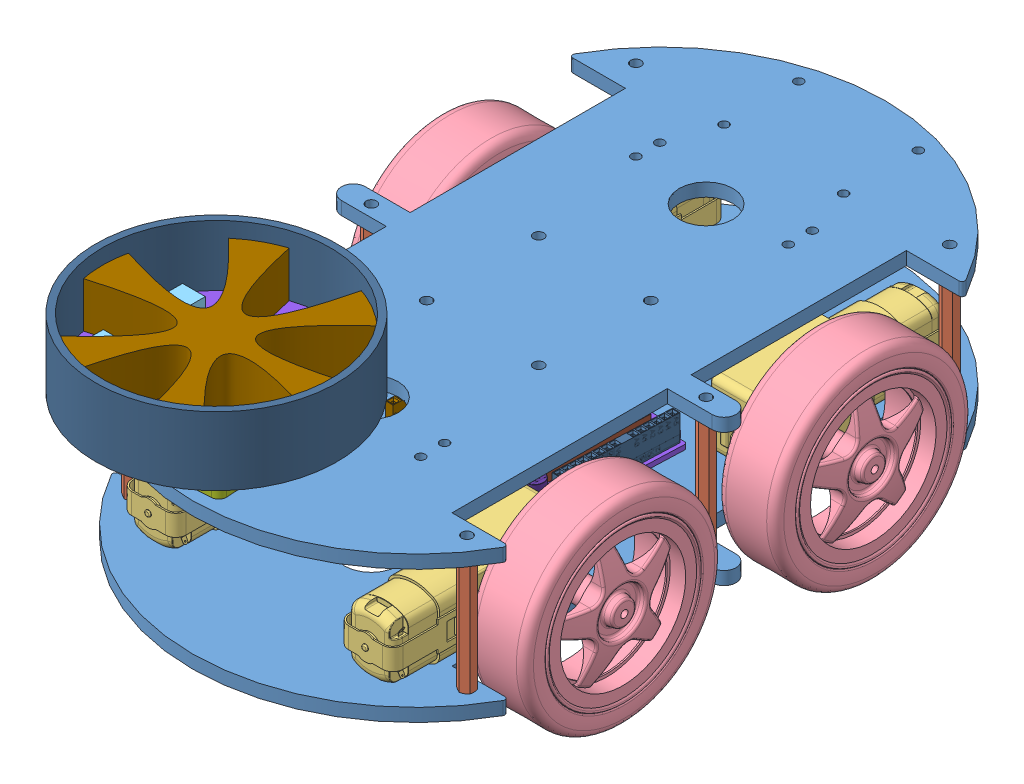
SolidWorks assembly new mechanical dispensing system, configuration Default. Lengths in mm.
Overall size (144 125.53 276.26).
42 component instances, 28 part files, 52 mates.
Components (placement in the parent):
- Base Plate-1: Base Plate [Default] at origin size (132 4.4 231.81)
- Long Hex Nut-1: Long Hex Nut [B18.2.4.1M - Hex nut, Style 1,  M3 x 0.5 --D-N] at (-56 44.4 80) x (-0.471141 0 -0.882058) z (0 1 0) size (4.5 5.2 40)
- Long Hex Nut-5: Long Hex Nut [B18.2.4.1M - Hex nut, Style 1,  M3 x 0.5 --D-N] at (56 44.4 0) x (1 0 0) z (0 1 0) size (4.5 5.2 40)
- Long Hex Nut-6: Long Hex Nut [B18.2.4.1M - Hex nut, Style 1,  M3 x 0.5 --D-N] at (56 44.4 80) x (1 0 0) z (0 1 0) size (4.5 5.2 40)
- Long Hex Nut-7: Long Hex Nut [B18.2.4.1M - Hex nut, Style 1,  M3 x 0.5 --D-N] at (52.5 44.4 -85) x (1 0 0) z (0 1 0) size (4.5 5.2 40)
- Long Hex Nut-8: Long Hex Nut [B18.2.4.1M - Hex nut, Style 1,  M3 x 0.5 --D-N] at (-52.5 44.4 -85) x (1 0 0) z (0 1 0) size (4.5 5.2 40)
- Long Hex Nut-9: Long Hex Nut [B18.2.4.1M - Hex nut, Style 1,  M3 x 0.5 --D-N] at (-56 44.4 0) x (1 0 0) z (0 1 0) size (4.5 5.2 40)
- Base Plate-2: Base Plate [Default] at (0 44.4 0) size (132 4.4 231.81)
- Motor-1: Motor [Predeterminado] at (37.6 15.65 -77.2352) x (0 0 1) z (-1 0 0) size (69.7 22.5 36.8)
- Motor-2: Motor [Predeterminado] at (37.6 15.65 80.1311) x (0 0 -1) z (1 0 0) size (69.7 22.5 36.8)
- Motor-3: Motor [Predeterminado] at (-37.6 15.65 77.5479) x (0 0 -1) z (1 0 0) size (69.7 22.5 36.8)
- Motor-4: Motor [Predeterminado] at (-37.6 15.65 -76) x (0 0 1) z (-1 0 0) size (69.7 22.5 36.8)
- Wheel-1: Wheel [Predeterminado] at (-52 15.65 -39.2) x (-1 0 0) z (0 -0.685524 -0.72805) size (25 66 66)
- Wheel-2: Wheel [Predeterminado] at (52 15.65 -40.4352) x (1 0 0) z (0 0.941369 0.337378) size (25 66 66)
- Wheel-3: Wheel [Predeterminado] at (-52 15.65 40.7479) x (-1 0 0) z (0 -0.719414 -0.694582) size (25 66 66)
- Wheel-4: Wheel [Predeterminado] at (52 15.65 43.3311) x (1 0 0) z (0 -0.162012 0.986789) size (25 66 66)
- cube-2: cube [Default] at (-27.6013 78.01 114.2712) size (7.62 7.62 7.62)
- cube-7: cube [Default] at (-27.7204 78.01 87.6337) size (7.62 7.62 7.62)
- Ardi_UNO.STEP-1: Ardi_UNO.STEP [Default] at (-32.6159 2.8 38.091) x (0.039139 0 -0.999234) z (0 1 0) size (76.36 53.4 14.04)
  - Pins_3fach_q_001.STEP-1: Pins_3fach_q_001.STEP [Default] at (64.19 -23.29 3.21) size (5.08 7.62 11.94)
  - Pins_3fach_q_002.STEP-1: Pins_3fach_q_002.STEP [Default] at (15.78 -9.32 3.21) x (0 1 0) z (0 0 1) size (5.08 7.62 11.94)
  - Ardi_UNO_Platine_001.STEP-1: Ardi_UNO_Platine_001.STEP [Default] at origin size (69 53.4 1.61)
  - Headers_digital_001.STEP-1: Headers_digital_001.STEP [Default] at origin size (47.8 2.55 10.95)
  - Headers_Analog_001.STEP-1: Headers_Analog_001.STEP [Default] at origin size (38.85 2.55 10.95)
  - atmega328_socket_001.STEP-1: atmega328_socket_001.STEP [Default] at origin size (35.5 10 6.2)
  - atmega328_001.STEP-1: atmega328_001.STEP [Default] at origin size (35.36 8.18 5.99)
  - resetButton UNO_001.STEP-1: resetButton UNO_001.STEP [Default] at origin size (8.5 6.5 3.8)
  - USB_typeB_001.STEP-1: USB_typeB_001.STEP [Default] at (8.29 -16.56 3.2) x (0 -1 0) z (0 0 1) size (12.06 16.98 13.98)
  - Stromanschluss_arduino UNO_001.STEP-1: Stromanschluss_arduino UNO_001.STEP [Default] at origin size (14.2 9.2 13)
  - Kondensator_A8-47-25V_001.STEP-1: Kondensator_A8-47-25V_001.STEP [Default] at (-0.25 0 0) size (6.5 7.5 5)
  - Kondensator_A8-47-25V_002.STEP-1: Kondensator_A8-47-25V_002.STEP [Default] at (6.5 0 0) size (6.5 7.5 5)
  - Quarz_Arduino_16_001.STEP-1: Quarz_Arduino_16_001.STEP [Default] at origin size (12.5 4.5 5.2)
  - Transistor Arduino UNO_001.STEP-1: Transistor Arduino UNO_001.STEP [Default] at origin size (6.8 6.5 1.6)
  - LED Arduino UNO gelb_001.STEP-1: LED Arduino UNO gelb_001.STEP [Default] at origin size (2 1 0.5)
  - LED Arduino UNO gelb_002.STEP-1: LED Arduino UNO gelb_002.STEP [Default] at (0 -6 0) size (2 1 0.5)
  - LED Arduino UNO gelb_003.STEP-1: LED Arduino UNO gelb_003.STEP [Default] at (0 -8 0) size (2 1 0.5)
  - LED Arduino UNO gr__n_001.STEP-1: LED Arduino UNO gr__n_001.STEP [Default] at (30.5 -6 0) size (2 1 0.5)
  - achterTeil_001.STEP-1: achterTeil_001.STEP [Default] at origin size (3.2 4.7 0.8)
- stepper motor-2: stepper motor [Default] at (-4.4982 66.58 103.3442) x (-0.060615 0 -0.998161) z (0 -1 0) size (17.78 17.78 25.4)
- dispensing system disc-1: dispensing system disc [Default] at (-4.4982 71.66 103.3442) x (-0.818866 0 0.573984) z (0 1 0) size (76.2 76.19 2.54)
- new dispensing system-1: new dispensing system [Default] at (-4.4982 74.2 103.3442) x (-0.999945 0 -0.010458) z (0 1 0) size (76.2 72.18 15.24)
- dispensing shell-1: dispensing shell [Default] at (-4.4982 94.52 103.3442) x (0.738984 0 -0.673723) z (0 -1 0) size (80.71 80.71 22.86)
Mates (geometry in assembly coordinates):
- Coincident11: coincident anti-aligned: plane of Base Plate-1 through (0 4.4 0) normal (0 1 0); plane of Long Hex Nut-1 through (-53.8799 4.4 83.9693) normal (0 -1 0)
- Concentric1: concentric anti-aligned: circle of Base Plate-1; circle of Long Hex Nut-1
- Concentric21: concentric anti-aligned: cylinder of Base Plate-1 through (-18.75 0 18.75) axis (0 -1 0) radius 1.75; cylinder of Long Hex Nut-2 through (-18.75 19.3625 18.75) axis (0 1 0) radius 1.5
- Coincident21: coincident anti-aligned: plane of Base Plate-1 through (0 4.4 0) normal (0 1 0); plane of Long Hex Nut-2 through (-23.25 4.4 18.75) normal (0 -1 0)
- Coincident31: coincident anti-aligned: plane of Base Plate-1 through (0 4.4 0) normal (0 1 0); plane of Long Hex Nut-3 through (-27.4259 4.4 -36.2608) normal (0 -1 0)
- Concentric31: concentric anti-aligned: cylinder of Base Plate-1 through (20 0 -82) axis (0 -1 0) radius 1.5; cylinder of Long Hex Nut-4 through (20 19.3625 -82) axis (0 1 0) radius 1.5
- Coincident41: coincident anti-aligned: plane of Base Plate-1 through (0 4.4 0) normal (0 1 0); plane of Long Hex Nut-4 through (15.5 4.4 -82) normal (0 -1 0)
- Concentric41: concentric anti-aligned: cylinder of Base Plate-1 through (56 0 0) axis (0 -1 0) radius 1.75; cylinder of Long Hex Nut-5 through (56 19.3625 0) axis (0 1 0) radius 1.5
- Coincident51: coincident anti-aligned: plane of Base Plate-1 through (0 4.4 0) normal (0 1 0); plane of Long Hex Nut-5 through (51.5 4.4 0) normal (0 -1 0)
- Concentric51: concentric anti-aligned: cylinder of Base Plate-1 through (56 0 80) axis (0 -1 0) radius 1.75; cylinder of Long Hex Nut-6 through (56 19.3625 80) axis (0 1 0) radius 1.5
- Coincident61: coincident anti-aligned: plane of Base Plate-1 through (0 4.4 0) normal (0 1 0); plane of Long Hex Nut-6 through (51.5 4.4 80) normal (0 -1 0)
- Concentric81: concentric anti-aligned: cylinder of Base Plate-1 through (52.5 0 -85) axis (0 -1 0) radius 1.75; cylinder of Long Hex Nut-7 through (52.5 19.3625 -85) axis (0 1 0) radius 1.5
- Coincident71: coincident anti-aligned: plane of Base Plate-1 through (0 4.4 0) normal (0 1 0); plane of Long Hex Nut-7 through (48 4.4 -85) normal (0 -1 0)
- Concentric91: concentric anti-aligned: cylinder of Base Plate-1 through (-52.5 0 -85) axis (0 -1 0) radius 1.75; cylinder of Long Hex Nut-8 through (-52.5 19.3625 -85) axis (0 1 0) radius 1.5
- Coincident81: coincident anti-aligned: plane of Base Plate-1 through (0 4.4 0) normal (0 1 0); plane of Long Hex Nut-8 through (-57 4.4 -85) normal (0 -1 0)
- Concentric101: concentric anti-aligned: cylinder of Base Plate-1 through (-56 0 0) axis (0 -1 0) radius 1.75; cylinder of Long Hex Nut-9 through (-56 19.3625 0) axis (0 1 0) radius 1.5
- Coincident91: coincident anti-aligned: plane of Base Plate-1 through (0 4.4 0) normal (0 1 0); plane of Long Hex Nut-9 through (-60.5 4.4 0) normal (0 -1 0)
- Concentric11: concentric anti-aligned: circle of Long Hex Nut-1; cylinder of Base Plate-2 through (-56 44.4 80) axis (0 -1 0) radius 1.75
- Concentric12: concentric aligned: circle of Long Hex Nut-7; cylinder of Base Plate-2 through (52.5 44.4 -85) axis (0 -1 0) radius 1.75
- Coincident10: coincident anti-aligned: plane of Long Hex Nut-7 through (48 44.4 -85) normal (0 1 0); plane of Base Plate-2 through (0 44.4 0) normal (0 -1 0)
- Coincident11: coincident anti-aligned: plane of Base Plate-1 through (0 4.4 0) normal (0 1 0); plane of Motor-1 through (28.2 4.4 -31.5352) normal (0 -1 0)
- Coincident12: coincident aligned: plane of Base Plate-1 through (47 4.4 -76) normal (1 0 0); plane of Motor-1 through (47 6.7 -31.5352) normal (1 0 0)
- Coincident13: coincident anti-aligned: plane of Base Plate-1 through (0 4.4 0) normal (0 1 0); plane of Motor-4 through (-47 4.4 -30.3) normal (0 -1 0)
- Coincident14: coincident aligned: plane of Base Plate-1 through (-47 4.4 -76) normal (-1 0 0); plane of Motor-4 through (-47 6.7 -30.3) normal (-1 0 0)
- Coincident15: coincident anti-aligned: plane of Base Plate-1 through (0 4.4 0) normal (0 1 0); plane of Motor-3 through (-28.2 4.4 31.8479) normal (0 -1 0)
- Coincident16: coincident aligned: plane of Base Plate-1 through (-47 4.4 76) normal (-1 0 0); plane of Motor-3 through (-47 6.7 31.8479) normal (-1 0 0)
- Coincident17: coincident anti-aligned: plane of Base Plate-1 through (0 4.4 0) normal (0 1 0); plane of Motor-2 through (47 4.4 34.4311) normal (0 -1 0)
- Coincident18: coincident aligned: plane of Base Plate-1 through (47 4.4 76) normal (1 0 0); plane of Motor-2 through (47 6.7 34.4311) normal (1 0 0)
- Concentric13: concentric aligned: circle of Motor-2; circle of Wheel-4
- Coincident24: coincident aligned: circle of Motor-1; plane of Wheel-2 through (47 15.65 -40.4352) normal (-1 0 0)
- Parallel1: parallel anti-aligned: plane of Motor-1 through (56 15.65 -77.2352) normal (1 0 0); plane of Wheel-2 through (47 15.65 -40.4352) normal (-1 0 0)
- Coincident26: coincident anti-aligned: plane of Motor-2 through (47 6.7 34.4311) normal (1 0 0); plane of Wheel-4 through (47 15.65 43.3311) normal (-1 0 0)
- Coincident29: coincident anti-aligned: plane of Motor-1 through (47 6.7 -31.5352) normal (1 0 0); plane of Wheel-2 through (47 15.65 -40.4352) normal (-1 0 0)
- Concentric14: concentric anti-aligned: circle of Motor-1; circle of Wheel-2
- Concentric15: concentric aligned: circle of Motor-4; circle of Wheel-1
- Coincident30: coincident anti-aligned: plane of Motor-4 through (-47 6.7 -30.3) normal (-1 0 0); plane of Wheel-1 through (-47 15.65 -39.2) normal (1 0 0)
- Concentric16: concentric anti-aligned: circle of Motor-3; circle of Wheel-3
- Coincident31: coincident anti-aligned: plane of Motor-3 through (-47 6.7 31.8479) normal (-1 0 0); plane of Wheel-3 through (-47 15.65 40.7479) normal (1 0 0)
- Coincident35: coincident aligned: line of Base Plate-1 through (-47 4.4 -76) axis (0 -1 0); line of Motor-4 through (-47 21.9222 -76) axis (0 -1 0)
- Parallel4: parallel anti-aligned: line of Base Plate-1 through (47 4.4 -76) axis (0 -1 0); line of Motor-1 through (45.5 9.3778 -77.2352) axis (0 1 0)
- Coincident96: coincident anti-aligned: plane of Base Plate-1 through (0 4.4 0) normal (0 1 0); plane of Ardi_UNO.STEP-1/Ardi_UNO_Platine_001.STEP-1 through (-4.4777 4.4 5.4847) normal (0 -1 0)
- Coincident97: coincident: cylinder of Motor-4 through (-28.7 24.6 -28.5) axis (0 -1 0) radius 0.5; line of Ardi_UNO.STEP-1/Ardi_UNO_Platine_001.STEP-1 through (-28.2467 4.4 -28.2889) axis (0 1 0)
- Coincident98: coincident anti-aligned: plane of Base Plate-2 through (0 48.8 0) normal (0 1 0); plane of stepper motor-2 through (-4.4982 48.8 103.3442) normal (0 -1 0)
- Concentric102: concentric anti-aligned: cylinder of stepper motor-2 through (-4.4982 74.2 103.3442) axis (0 -1 0) radius 1.5744; cylinder of dispensing system disc-1 through (-4.4982 71.66 103.3442) axis (0 1 0) radius 1.524
- Coincident99: coincident anti-aligned: plane of dispensing system disc-1 through (-4.4982 74.2 103.3442) normal (0 1 0); plane of new dispensing system-1 through (-4.4982 74.2 103.3442) normal (0 -1 0)
- Coincident100: coincident anti-aligned: plane of stepper motor-2 through (-4.4982 74.2 103.3442) normal (0 1 0); plane of new dispensing system-1 through (-4.4982 74.2 103.3442) normal (0 -1 0)
- Coincident102: coincident anti-aligned: plane of cube-2 through (-31.4113 74.2 121.8912) normal (0 -1 0); plane of dispensing system disc-1 through (-4.4982 74.2 103.3442) normal (0 1 0)
- Coincident103: coincident anti-aligned: plane of cube-7 through (-31.5304 74.2 95.2537) normal (0 -1 0); plane of dispensing system disc-1 through (-4.4982 74.2 103.3442) normal (0 1 0)
- Coincident104: coincident aligned: plane of dispensing system disc-1 through (-4.4982 71.66 103.3442) normal (0 -1 0); plane of dispensing shell-1 through (-4.4982 71.66 103.3442) normal (0 -1 0)
- Parallel5: parallel aligned: plane of new dispensing system-1 through (-4.5999 89.44 113.0682) normal (0 1 0); plane of dispensing shell-1 through (-4.4982 94.52 103.3442) normal (0 1 0)
- Concentric104: concentric anti-aligned: circle of dispensing system disc-1; circle of dispensing shell-1
- Concentric105: concentric aligned: circle of dispensing system disc-1; circle of new dispensing system-1
